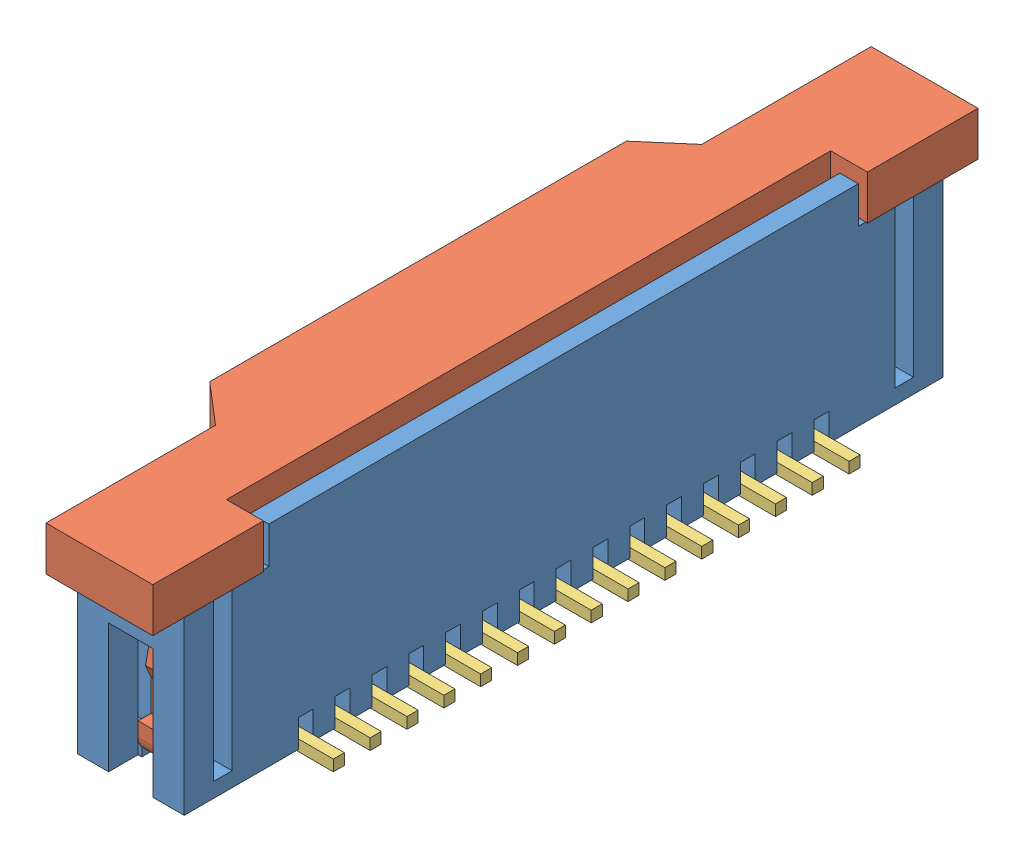
SolidWorks assembly FCC-Verbinder, configuration Valor predeterminado. Lengths in mm.
Overall size (4.85 6 22.4).
17 component instances, 3 part files, 5 mates.
Components (placement in the parent):
- FCC-Inner-1: FCC-Inner [Valor predeterminado] at (-100.5372 19.1242 0) size (2.9 5.7 20.6)
- FCC-Stopper-1: FCC-Stopper [Valor predeterminado] at (-101.0372 23.8242 0) size (4 5.4 22.4)
- FCC-Pin-1: FCC-Pin [Valor predeterminado] at (-100.5372 19.1242 7.15) x (-1 0 0) z (0 0 -1) size (4.3 4.71 0.3)
- FCC-Pin-2: FCC-Pin [Valor predeterminado] at (-100.5372 19.1242 6.15) x (-1 0 0) z (0 0 -1) size (4.3 4.71 0.3)
- FCC-Pin-3: FCC-Pin [Valor predeterminado] at (-100.5372 19.1242 5.15) x (-1 0 0) z (0 0 -1) size (4.3 4.71 0.3)
- FCC-Pin-4: FCC-Pin [Valor predeterminado] at (-100.5372 19.1242 4.15) x (-1 0 0) z (0 0 -1) size (4.3 4.71 0.3)
- FCC-Pin-5: FCC-Pin [Valor predeterminado] at (-100.5372 19.1242 3.15) x (-1 0 0) z (0 0 -1) size (4.3 4.71 0.3)
- FCC-Pin-6: FCC-Pin [Valor predeterminado] at (-100.5372 19.1242 2.15) x (-1 0 0) z (0 0 -1) size (4.3 4.71 0.3)
- FCC-Pin-7: FCC-Pin [Valor predeterminado] at (-100.5372 19.1242 1.15) x (-1 0 0) z (0 0 -1) size (4.3 4.71 0.3)
- FCC-Pin-8: FCC-Pin [Valor predeterminado] at (-100.5372 19.1242 0.15) x (-1 0 0) z (0 0 -1) size (4.3 4.71 0.3)
- FCC-Pin-9: FCC-Pin [Valor predeterminado] at (-100.5372 19.1242 -0.85) x (-1 0 0) z (0 0 -1) size (4.3 4.71 0.3)
- FCC-Pin-10: FCC-Pin [Valor predeterminado] at (-100.5372 19.1242 -1.85) x (-1 0 0) z (0 0 -1) size (4.3 4.71 0.3)
- FCC-Pin-11: FCC-Pin [Valor predeterminado] at (-100.5372 19.1242 -2.85) x (-1 0 0) z (0 0 -1) size (4.3 4.71 0.3)
- FCC-Pin-12: FCC-Pin [Valor predeterminado] at (-100.5372 19.1242 -3.85) x (-1 0 0) z (0 0 -1) size (4.3 4.71 0.3)
- FCC-Pin-13: FCC-Pin [Valor predeterminado] at (-100.5372 19.1242 -4.85) x (-1 0 0) z (0 0 -1) size (4.3 4.71 0.3)
- FCC-Pin-14: FCC-Pin [Valor predeterminado] at (-100.5372 19.1242 -5.85) x (-1 0 0) z (0 0 -1) size (4.3 4.71 0.3)
- FCC-Pin-15: FCC-Pin [Valor predeterminado] at (-100.5372 19.1242 -6.85) x (-1 0 0) z (0 0 -1) size (4.3 4.71 0.3)
Mates (geometry in assembly coordinates):
- Coincidente1: coincident anti-aligned: plane of FCC-Inner-1 through (-100.5372 23.8242 0) normal (0 1 0); plane of FCC-Stopper-1 through (-101.0372 23.8242 0) normal (0 -1 0)
- Coincidente2: coincident anti-aligned: plane of FCC-Inner-1 through (-100.0372 19.5242 9.8) normal (-1 0 0); plane of FCC-Stopper-1 through (-100.0372 25.0242 -8.2) normal (1 0 0)
- Distância6: distance = 0.5 mm aligned: plane of FCC-Inner-1 through (-101.9872 23.8242 10.3) normal (-1 0 0); plane of FCC-Pin-1 through (-102.4872 19.3242 6.85) normal (-1 0 0)
- Distância7: distance = 0.1 mm aligned: plane of FCC-Inner-1 through (-100.5372 19.1242 0) normal (0 -1 0); plane of FCC-Pin-1 through (-102.4872 19.0242 6.85) normal (0 -1 0)
- Distância8: distance = 0.05 mm anti-aligned: plane of FCC-Pin-1 through (-100.5372 19.1242 7.15) normal (0 0 1); plane of FCC-Inner-1 through (-101.4872 25.8242 7.2) normal (0 0 -1)
